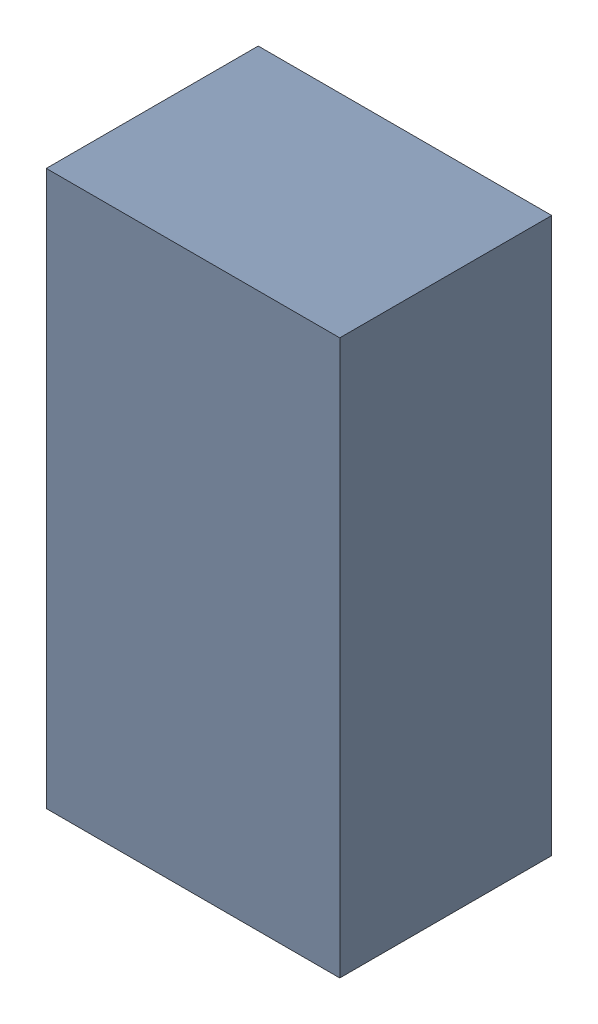
SolidWorks assembly C210, configuration Standard. Lengths in mm.
Overall size (1.8 3.4 1.3).
2 component instances, 1 part files, 0 mates.
Components (placement in the parent):
- 885541968-1: 885541968 [Standard] at (2.93 -17.7 0) size (1.8 3.4 1.3)
  - Extruded_30-1: Extruded_30 [Standard] at origin size (1.8 3.4 1.3)
